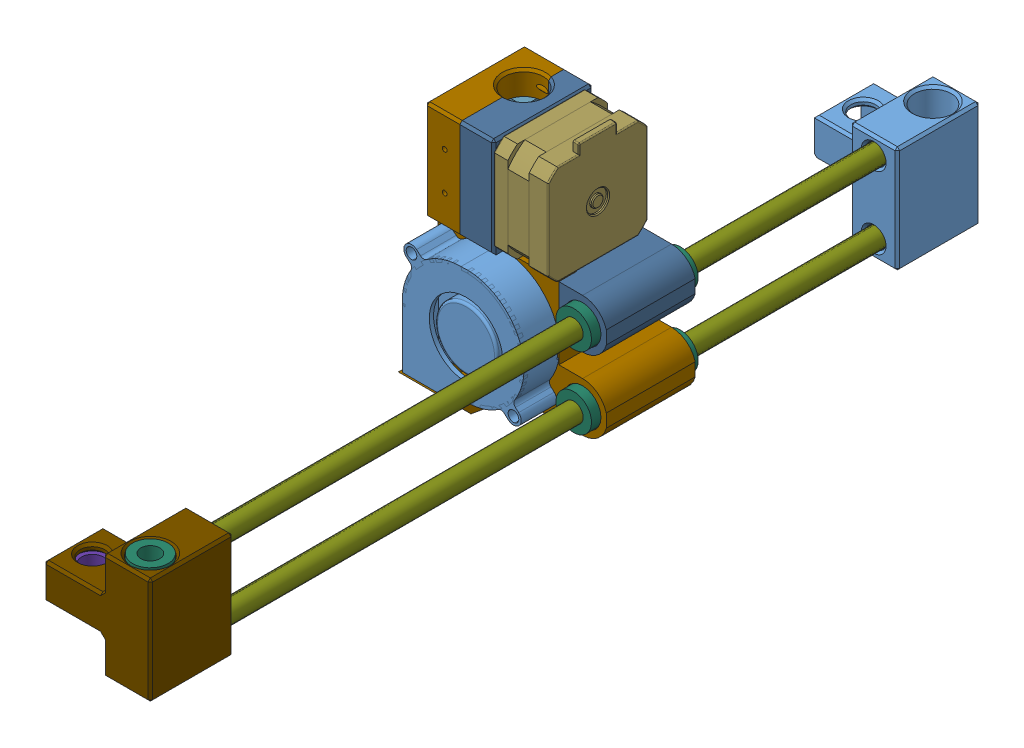
SolidWorks assembly Printer, configuration Default. Lengths in mm.
Overall size (82.8 112.6 350).
26 component instances, 19 part files, 17 mates.
Components (placement in the parent):
- Extruder-1: Extruder [Default] at (7.6222 18.123 107.7583) size (82.8 112.6 60.72)
  - Extruder fan-1: Extruder fan [Default] at origin size (51.32 51.11 15)
    - CoverBottom^Extruder fan-1: CoverBottom^Extruder fan [Default] at origin size (51.32 51.11 15) (virtual)
  - E3D-1: E3D [Default] at (-15.65 6.8806 -22.5) size (28.67 62.35 25.33)
    - E3D Heat Block-1: E3D Heat Block [Default] at origin size (20 12 16)
    - E3D Heatbreak-1: E3D Heatbreak [Default] at (-6 19.55 0) x (-0.93266 0 -0.360757) z (-0.360757 0 0.93266) size (6 25.1 6)
    - E3D Nozzle-1: E3D Nozzle [Default] at (-6 -3.5 0) x (-0.097107 0 -0.995274) z (0.995274 0 -0.097107) size (9.24 12.5 8)
    - E3D Heatsink-1: E3D Heatsink [1.75 Bowden] at (-6 35.475 0) x (0.986263 0 -0.165183) z (0.165183 0 0.986263) size (22 42.75 22)
    - cartridge heater-1: cartridge heater [Default] at (1 7 0) x (0 0 1) z (-0.150948 -0.988542 0) size (32 6.2 6.2)
    - thermistor-1: thermistor [Default] at (-8 2 6.5) x (-0.997586 0.069447 0) z (-0.069447 -0.997586 0) size (2 13.25 2)
  - 30mm fan-1: 30mm fan [Default] at (-46.74 31.8556 -22.5) x (0 0 -1) z (1 0 0) size (30 30 10.44)
    - Component1.step-1: Component1.step [Default] at origin size (30 30 10.44)
  - Fan shroud-1: Fan shroud [Default] at (-36.4 16.8556 -37.5) x (0 0 1) z (-1 0 0) size (53.2 105.2 72)
  - Extruder-1: Extruder [Default] at (-7.4 59.9806 -7.5) x (0 0 -1) z (1 0 0) size (42 62.75 57.81)
  - Extruder drive gear-1: Extruder drive gear [Default] at (-21.65 88.9806 -16.5) x (-1 0 0) z (0 0.036827 -0.999322) size (11 12 12.01)
  - Extruder stepper-1: Extruder stepper [NEMA 17 L34] at (-7.4 88.9806 -16.5) x (0 0 -1) z (1 0 0) size (42 46 47)
  - Filament bearing-1: Filament bearing [Default] at (-21.6656 90.7306 -31.838) x (0 -0.139313 -0.990248) z (0 -0.990248 0.139313) size (15.88 3.97 15.88)
  - Bearing holder-1: Bearing holder [Default] at (-16.0563 77.7306 -45.0225) x (0 0 1) z (0 -1 0) size (20 16 22)
  - Slide bearing-1: Slide bearing [Default] at (25.6 27.2306 3.75) x (-0.926759 -0.375657 0) z (0.375657 -0.926759 0) size (15 45 15)
  - Slide bearing-2: Slide bearing [Default] at (25.6 57.6056 3.75) x (-0.813252 0.581911 0) z (-0.581911 -0.813252 0) size (15 45 15)
- Slider rod-1: Slider rod [Default] at (33.2222 75.7287 275.0226) x (0 0 -1) z (0.48936 -0.872082 0) size (300 8 8)
- Slider rod-2: Slider rod [Default] at (33.2222 45.3537 275.0226) x (0 0 -1) z (1 0 0) size (300 8 8)
- Slide bearing-1: Slide bearing [Default] at (33.2222 38.0412 290.0226) x (0.961576 0 0.274539) z (-0.274539 0 0.961576) size (15 45 15)
- Nut-1: Nut [Default] at (6.3051 56.3912 287.5226) x (0 0 1) z (-1 0 0) size (14 8.3 16.17)
- Slide rod holder-1: Slide rod holder [Default] at (43.2222 38.0412 300.0226) x (0 0 -1) z (1 0 0) size (35 45 45)
- Slide rod holder A-1: Slide rod holder A [Default] at (43.2222 38.0412 -14.9774) x (0 0 -1) z (1 0 0) size (35 45 45)
Mates (geometry in assembly coordinates):
- Concentric1: concentric anti-aligned: circle of Extruder-1/Slide bearing-1; cylinder of Slider rod-2 through (33.2222 45.3537 -24.9774) axis (0 0 1) radius 4
- Concentric2: concentric anti-aligned: circle of Extruder-1/Slide bearing-2; cylinder of Slider rod-1 through (33.2222 75.7287 -24.9774) axis (0 0 1) radius 4
- Coincident3: coincident aligned: plane of Slider rod-1 through (33.2222 75.7287 275.0226) normal (0 0 1); plane of Slider rod-2 through (33.2222 45.3537 275.0226) normal (0 0 1)
- Parallel2: parallel aligned: plane of Extruder-1/Extruder-1 through (6.2222 128.1037 108.2288) normal (0 1 0); plane of Slide bearing-1 through (33.2222 83.0412 290.0226) normal (0 1 0)
- Concentric3: concentric anti-aligned: cylinder of Slide bearing-1 through (33.2222 83.0412 290.0226) axis (0 -1 0) radius 7.5; cylinder of Slide rod holder-1 through (33.2222 38.0412 290.0226) axis (0 1 0) radius 7.75
- Parallel3: parallel anti-aligned: plane of Slider rod-2 through (33.2222 45.3537 275.0226) normal (0 0 1); plane of Slide rod holder-1 through (43.2222 83.0412 265.0226) normal (0 0 -1)
- Width1: width: plane of Slide rod holder-1 through (43.2222 83.0412 300.0226) normal (1 0 0); plane of Slide rod holder-1 through (23.2222 83.0412 300.0226) normal (-1 0 0); cylinder of Slider rod-2 through (33.2222 45.3537 -24.9774) axis (0 0 1) radius 4
- Width2: width aligned: plane of Slide rod holder-1 through (43.2222 38.0412 300.0226) normal (0 -1 0); plane of Slide rod holder-1 through (43.2222 83.0412 300.0226) normal (0 1 0); plane of Extruder-1/Fan shroud-1 through (-28.7778 34.9787 70.2583) normal (0 -1 0); plane of Extruder-1/Extruder-1 through (59.6991 86.1037 70.2583) normal (0 1 0)
- Width3: width anti-aligned: plane of Slide bearing-1 through (33.2222 83.0412 290.0226) normal (0 1 0); plane of Slide bearing-1 through (33.2222 38.0412 290.0226) normal (0 -1 0); plane of Slide rod holder-1 through (43.2222 38.0412 300.0226) normal (0 -1 0); plane of Slide rod holder-1 through (43.2222 83.0412 300.0226) normal (0 1 0)
- Coincident11: coincident anti-aligned: plane of Slider rod-1 through (33.2222 75.7287 275.0226) normal (0 0 1); plane of Slide rod holder-1 through (33.2222 75.7287 275.0226) normal (0 0 -1)
- Coincident12: coincident aligned: line of Nut-1 through (-1.7778 64.6912 287.5226) axis (0 -1 0); plane of Slide rod holder-1 through (-1.7778 38.0412 300.0226) normal (-1 0 0)
- Parallel4: parallel aligned: plane of Nut-1 through (10.3466 64.6912 280.5226) normal (0 0 -1); plane of Slide rod holder-1 through (-1.7778 53.0412 275.0226) normal (0 0 -1)
- Width5: width anti-aligned: plane of Nut-1 through (10.3466 64.6912 280.5226) normal (0 0 -1); plane of Nut-1 through (2.2637 64.6912 294.5226) normal (0 0 1); plane of Slide rod holder-1 through (43.2222 83.0412 300.0226) normal (0 0 1); plane of Slide rod holder-1 through (-1.7778 53.0412 275.0226) normal (0 0 -1)
- Width6: width anti-aligned: plane of Nut-1 through (6.3051 64.6912 287.5226) normal (0 1 0); plane of Nut-1 through (6.3051 56.3912 287.5226) normal (0 -1 0); plane of Slide rod holder-1 through (-1.7778 53.0412 300.0226) normal (0 -1 0); plane of Slide rod holder-1 through (-1.7778 68.0412 300.0226) normal (0 1 0)
- Coincident13: coincident aligned: plane of Slide rod holder-1 through (23.2222 83.0412 300.0226) normal (-1 0 0); plane of Slide rod holder A-1 through (23.2222 83.0412 -14.9774) normal (-1 0 0)
- Coincident14: coincident aligned: plane of Slide rod holder-1 through (43.2222 83.0412 300.0226) normal (0 1 0); plane of Slide rod holder A-1 through (43.2222 83.0412 -14.9774) normal (0 1 0)
- Coincident15: coincident anti-aligned: plane of Slider rod-1 through (33.2222 75.7287 -24.9774) normal (0 0 -1); plane of Slide rod holder A-1 through (33.2222 75.7287 -24.9774) normal (0 0 1)
